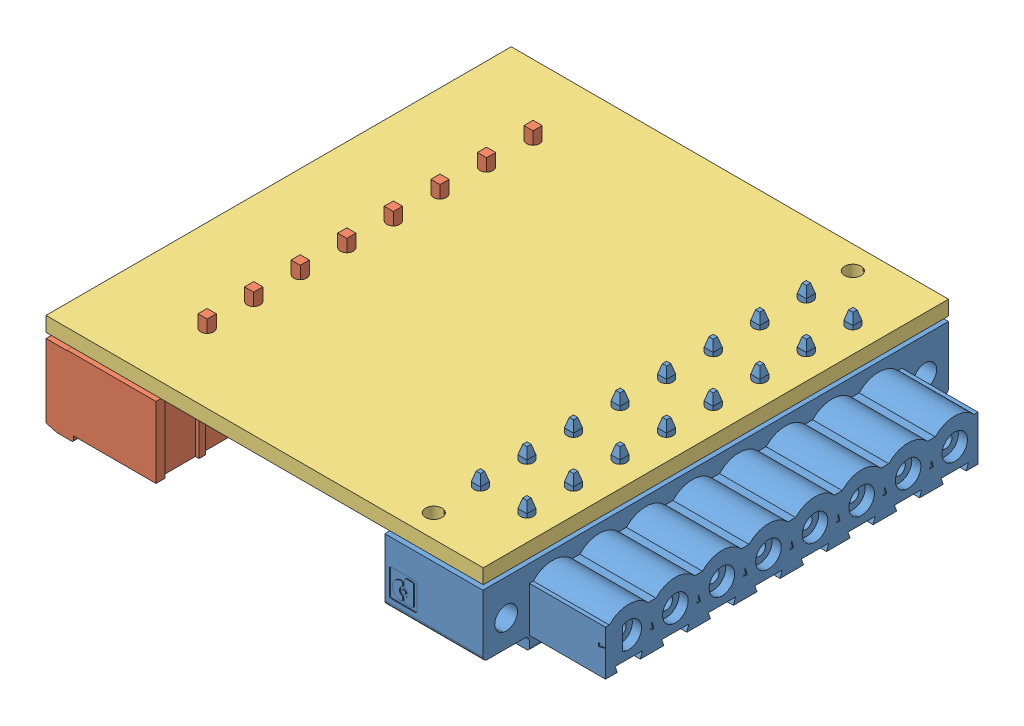
SolidWorks assembly X-K2510RH, configuration Default. Lengths in mm.
Overall size (56 13.7 50.8).
3 component instances, 3 part files, 3 mates.
Components (placement in the parent):
- 1825187-1: 1825187 [Default] at (-133.8619 10.4858 2.6809) size (19 13.7 50.8)
- c-796866-8-b1-3d-1: c-796866-8-b1-3d [Default] at (-147.6714 37.5871 27.4872) x (0 0 -1) z (-1 0 0) size (50.72 11.85 12)
- Part142-1: Part142 [Default] at (0 41.9721 0) x (1 0 0) z (0 1 0) size (47.7 50.76 1.6)
Mates (geometry in assembly coordinates):
- Parallel1: parallel anti-aligned: plane of 1825187-1 through (-110.6714 41.4721 2.0872) normal (-1 0 0); plane of c-796866-8-b1-3d-1 through (-135.6714 41.5921 53.8616) normal (1 0 0)
- Distance1: distance = 25 mm anti-aligned: plane of c-796866-8-b1-3d-1 through (-135.6714 41.5921 53.8616) normal (1 0 0); plane of 1825187-1 through (-110.6714 41.4721 2.0872) normal (-1 0 0)
- Concentric3: concentric aligned: circle of 1825187-1; circle of c-796866-8-b1-3d-1
